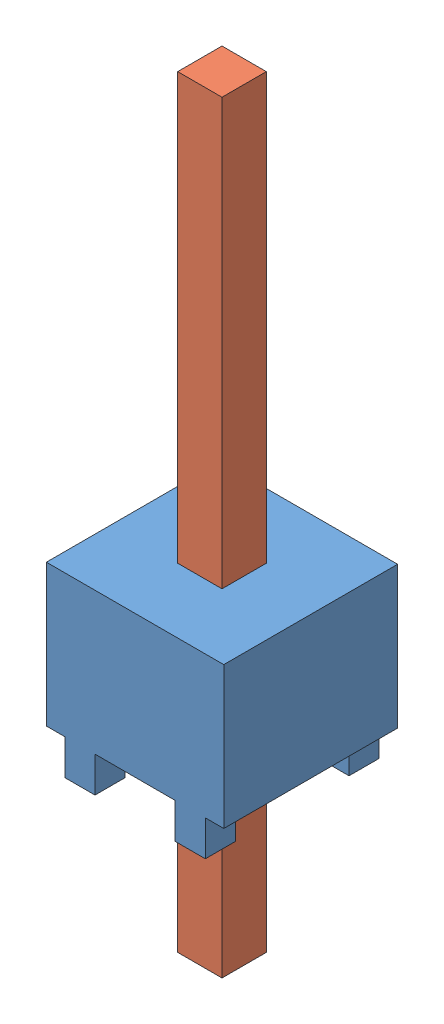
SolidWorks assembly HMTSW_101_07_G_S_240, configuration Default. Lengths in mm.
Overall size (2.54 10.92 2.49).
2 component instances, 2 part files, 0 mates.
Components (placement in the parent):
- _HMTSW_101_07_G_S_240_body_2-1: _HMTSW_101_07_G_S_240_body_2 [Default] at origin size (2.54 2.54 2.49)
- _HMTSW_101_07_S_240_4-1: _HMTSW_101_07_S_240_4 [Default] at (0 -2.286 0) size (0.89 10.92 0.89)
